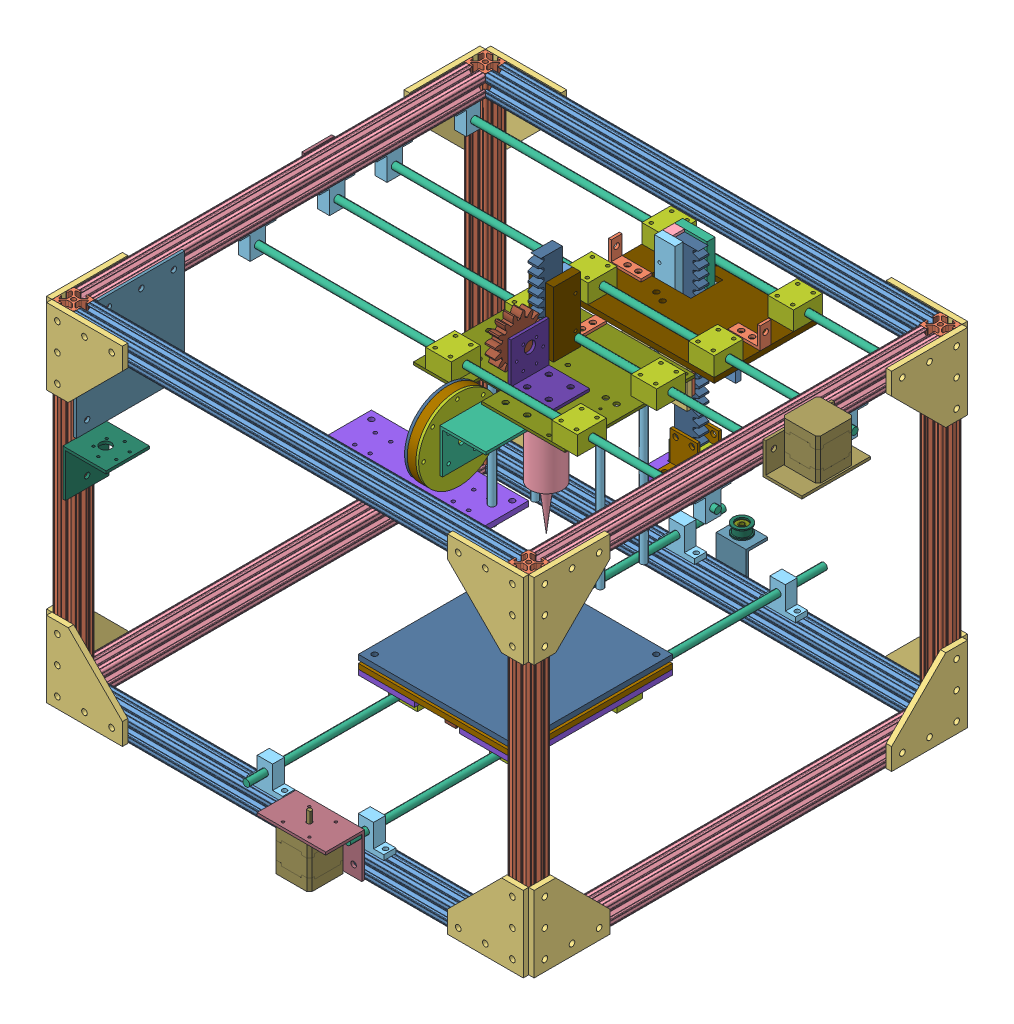
SolidWorks assembly V2, configuration Default. Lengths in mm.
Overall size (631.82 453.25 588.02).
124 component instances, 46 part files, 45 mates.
Components (placement in the parent):
- frame_asm-1: frame_asm [Default] at (279.5484 -24.8965 33.4997) size (571.5 406.4 520.7)
  - 8020-20in-3: 8020-20in [Default] at (-420.1656 190.7852 170.939) x (0 0 1) z (-1 0 0) size (25.4 25.4 508)
  - 8020-20in-4: 8020-20in [Default] at (-420.1656 190.7852 653.539) x (0 0 1) z (-1 0 0) size (25.4 25.4 508)
  - 8020-12in-1: 8020-12in [Default] at (-432.8656 178.0852 653.539) x (1 0 0) z (0 -1 0) size (25.4 25.4 406.4)
  - 8020-12in-2: 8020-12in [Default] at (100.5344 178.0852 653.539) x (-1 0 0) z (0 -1 0) size (25.4 25.4 406.4)
  - 8020-12in-3: 8020-12in [Default] at (-432.8656 584.4852 170.939) x (-1 0 0) z (0 1 0) size (25.4 25.4 406.4)
  - 8020-12in-4: 8020-12in [Default] at (100.5344 584.4852 170.939) x (-1 0 0) z (0 1 0) size (25.4 25.4 406.4)
  - 8020-20in-7: 8020-20in [Default] at (-420.1656 571.7852 653.539) x (0 0 1) z (-1 0 0) size (25.4 25.4 508)
  - 8020-20in-8: 8020-20in [Default] at (-420.1656 571.7852 170.939) x (0 0 1) z (-1 0 0) size (25.4 25.4 508)
  - corner bracket-1: corner bracket [Default] at (113.2344 178.0852 672.589) x (-1 0 0) z (0 0 -1) size (88.9 88.9 6.35)
  - corner bracket-2: corner bracket [Default] at (113.2344 584.4852 666.239) x (-1 0 0) z (0 0 1) size (88.9 88.9 6.35)
  - corner bracket-3: corner bracket [Default] at (119.5844 584.4852 666.239) x (0 0 -1) z (-1 0 0) size (88.9 88.9 6.35)
  - corner bracket-4: corner bracket [Default] at (113.2344 178.0852 666.239) x (0 0 -1) z (1 0 0) size (88.9 88.9 6.35)
  - corner bracket-5: corner bracket [Default] at (119.5844 178.0852 158.239) x (0 0 1) z (-1 0 0) size (88.9 88.9 6.35)
  - corner bracket-6: corner bracket [Default] at (113.2344 178.0852 158.239) x (-1 0 0) z (0 0 -1) size (88.9 88.9 6.35)
  - corner bracket-7: corner bracket [Default] at (113.2344 584.4852 151.889) x (-1 0 0) z (0 0 1) size (88.9 88.9 6.35)
  - corner bracket-8: corner bracket [Default] at (113.2344 584.4852 158.239) x (0 0 1) z (1 0 0) size (88.9 88.9 6.35)
  - corner bracket-9: corner bracket [Default] at (-445.5656 178.0852 666.239) size (88.9 88.9 6.35)
  - corner bracket-10: corner bracket [Default] at (-451.9156 178.0852 666.239) x (0 0 -1) z (1 0 0) size (88.9 88.9 6.35)
  - corner bracket-11: corner bracket [Default] at (-445.5656 584.4852 672.589) x (1 0 0) z (0 0 -1) size (88.9 88.9 6.35)
  - corner bracket-12: corner bracket [Default] at (-445.5656 584.4852 666.239) x (0 0 -1) z (-1 0 0) size (88.9 88.9 6.35)
  - corner bracket-13: corner bracket [Default] at (-445.5656 178.0852 151.889) size (88.9 88.9 6.35)
  - corner bracket-14: corner bracket [Default] at (-445.5656 178.0852 158.239) x (0 0 1) z (-1 0 0) size (88.9 88.9 6.35)
  - corner bracket-15: corner bracket [Default] at (-445.5656 584.4852 158.239) x (0 -1 0) z (-1 0 0) size (88.9 88.9 6.35)
  - corner bracket-16: corner bracket [Default] at (-445.5656 584.4852 158.239) x (1 0 0) z (0 0 -1) size (88.9 88.9 6.35)
  - 8020-18in-1: 8020-18in [Default] at (100.5344 190.7852 640.839) size (25.4 25.4 457.2)
  - 8020-18in-2: 8020-18in [Default] at (100.5344 571.7852 640.839) size (25.4 25.4 457.2)
  - 8020-18in-3: 8020-18in [Default] at (-432.8656 571.7852 640.839) size (25.4 25.4 457.2)
  - 8020-18in-4: 8020-18in [Default] at (-432.8656 190.7852 640.839) size (25.4 25.4 457.2)
- rails_asm-bottom-1: rails_asm-bottom [Default] at (188.2466 178.4066 647.1595) size (184.15 52.16 558.8)
  - Linear Rail Shaft Guide-1: Linear Rail Shaft Guide [Default] at (-12.9326 0.1821 32.8794) size (42 32.8 14)
  - Linear Rail Shaft Guide-2: Linear Rail Shaft Guide [Default] at (-12.9326 0.1821 -449.7206) size (42 32.8 14)
  - Linear Rail Shaft Guide-3: Linear Rail Shaft Guide [Default] at (-131.3326 0.1821 32.8794) size (42 32.8 14)
  - Linear Rail Shaft Guide-4: Linear Rail Shaft Guide [Default] at (-131.3326 0.1821 -449.7206) size (42 32.8 14)
  - 8mm rod-1: 8mm rod [Default] at (8.0674 20.1821 -489.9705) x (0.986971 -0.1609 0) z (0 0 1) size (8 8 558.8)
  - 8mm rod-2: 8mm rod [Default] at (-110.3326 20.1821 -489.9705) x (0.967966 -0.251082 0) z (0 0 1) size (8 8 558.8)
  - linear bearing platform-1: linear bearing platform [Default] at (-8.9326 9.1821 -144.8893) size (34 22 30)
  - linear bearing platform-2: linear bearing platform [Default] at (-8.9326 9.1821 -260.2393) size (34 22 30)
  - linear bearing platform-3: linear bearing platform [Default] at (-127.3326 9.1821 -144.8893) size (34 22 30)
  - linear bearing platform-4: linear bearing platform [Default] at (-127.3326 9.1821 -260.2393) size (34 22 30)
  - bottom plate-1: bottom plate [Default] at (-24.8076 37.1765 -279.6393) x (1 0 0) z (0 -1 0) size (65.75 184.15 5.99)
  - bottom plate-2: bottom plate [Default] at (-143.2076 37.1765 -279.6393) x (1 0 0) z (0 -1 0) size (65.75 184.15 5.99)
  - middle plate-1: middle plate [Default] at (-143.2076 37.1765 -95.4893) x (1 0 0) z (0 1 0) size (184.15 184.15 5.99)
  - top layer-1: top layer [Default] at (-143.2076 46.3459 -95.4893) x (1 0 0) z (0 1 0) size (184.15 184.15 5.99)
  - L-bracket belt mount-1: L-bracket belt mount [Default] at (-51.1326 37.1765 -257.4143) x (0 -1 0) z (-1 0 0) size (25.4 28.57 12.7)
  - L-bracket belt mount-2: L-bracket belt mount [Default] at (-63.8326 37.1765 -117.7143) x (0 -1 0) z (1 0 0) size (25.4 28.57 12.7)
- stepper motor-1: stepper motor [Default] at (160.1312 153.1887 724.0637) x (-1 0 0) z (0 1 0) size (42.3 42.3 63.5)
- L-bracket motor mount-1: L-bracket motor mount [Default] at (200.3312 153.1887 699.7387) x (0 0 1) z (-1 0 0) size (45.48 51.17 80.4)
- L-bracket idler mount-1: L-bracket idler mount [Default] at (104.6172 153.1887 191.7387) x (0 0 -1) z (1 0 0) size (25.4 51.17 34.92)
- idler pulley-1: idler pulley [Default] at (122.0797 211.3637 179.0387) x (0 -1 0) z (0.480075 0 0.877227) size (12.6 21 21)
  - B17023-1: B17023 [Default] at origin size (11.2 21 21)
  - BEARING_5_16_5-1: BEARING_5_16_5 [Default] at (-1.5 0 0) x (0 1 0) z (0 0 1) size (16 5 16)
  - B18026-1: B18026 [Default] at (2 0 0) x (0 1 0) z (0 0 1) size (10 1 10)
  - BEARING_5_16_5-2: BEARING_5_16_5 [Default] at (4.5 0 0) x (0 1 0) z (0 0 1) size (16 5 16)
- part placer asm-1: part placer asm [Default] at (270.0393 672.9206 180.4038) x (0 0 1) z (0 -1 0) size (135 558.8 245.72)
  - mounting plate-1: mounting plate [Default] at (27.1569 24.9758 169.7319) size (127 177.8 5.99)
  - front motor plate-1: front motor plate [Default] at (90.8368 139.2758 175.7263) x (0 -1 0) z (-1 0 0) size (76.2 50.8 5.99)
  - gearmotor mounting brackets-1: gearmotor mounting brackets [Default] at (141.8424 75.7758 175.7263) x (0 0 1) z (0 -1 0) size (38.1 25.4 12.7)
  - rear motor plate-1: rear motor plate [Default] at (147.8368 139.2758 175.7263) x (0 -1 0) z (-1 0 0) size (76.2 50.8 5.99)
  - rack back plate-1: rack back plate [Default] at (62.2477 151.5948 255.1013) x (1 0 0) z (0 1 0) size (13.97 127 11.81)
  - rack right plate-1: rack right plate [Default] at (85.7427 163.4058 255.1013) x (-1 0 0) z (0 -1 0) size (9.53 127 24.13)
  - rack left plate-1: rack left plate [Default] at (62.2477 163.4058 255.1013) x (-1 0 0) z (0 -1 0) size (9.53 127 38.1)
  - gearmotor mounting brackets-2: gearmotor mounting brackets [Default] at (141.8424 139.2758 175.7263) x (0 0 1) z (0 -1 0) size (38.1 25.4 12.7)
  - gearmotor mounting brackets-3: gearmotor mounting brackets [Default] at (90.8368 126.5758 175.7263) x (0 0 1) z (0 1 0) size (38.1 25.4 12.7)
  - gearmotor mounting brackets-4: gearmotor mounting brackets [Default] at (90.8368 63.0758 175.7263) x (0 0 1) z (0 1 0) size (38.1 25.4 12.7)
  - gearmotor mounting brackets-5: gearmotor mounting brackets [Default] at (85.7427 139.2758 175.7263) x (0 0 1) z (0 1 0) size (38.1 25.4 12.7)
  - gearmotor mounting brackets-6: gearmotor mounting brackets [Default] at (52.7227 144.3558 175.7263) x (0 0 1) z (0 -1 0) size (38.1 25.4 12.7)
  - rails_asm-1: rails_asm [Default] at (129.0895 -70.2762 138.5497) x (1 0 0) z (0 -1 0) size (135 32.8 558.8)
    - Linear Rail Shaft Guide-1: Linear Rail Shaft Guide [Default] at (-12.9326 0.1821 32.8794) size (42 32.8 14)
    - Linear Rail Shaft Guide-2: Linear Rail Shaft Guide [Default] at (-12.9326 0.1821 -500.7446) size (42 32.8 14)
    - Linear Rail Shaft Guide-3: Linear Rail Shaft Guide [Default] at (-105.9326 0.1821 32.8794) size (42 32.8 14)
    - Linear Rail Shaft Guide-4: Linear Rail Shaft Guide [Default] at (-105.9326 0.1821 -500.7446) size (42 32.8 14)
    - 8mm rod-1: 8mm rod [Default] at (8.0674 20.1821 -506.1132) x (0.336006 0.94186 0) z (0 0 1) size (8 8 558.8)
    - 8mm rod-2: 8mm rod [Default] at (-84.9326 20.1821 -506.1132) x (0.967966 -0.251082 0) z (0 0 1) size (8 8 558.8)
    - linear bearing platform-1: linear bearing platform [Default] at (-8.9326 9.1821 -125.252) size (34 22 30)
    - linear bearing platform-2: linear bearing platform [Default] at (-8.9326 9.1821 -273.052) size (34 22 30)
    - linear bearing platform-3: linear bearing platform [Default] at (-101.9326 9.1821 -125.252) size (34 22 30)
    - linear bearing platform-4: linear bearing platform [Default] at (-101.9326 9.1821 -273.052) size (34 22 30)
  - gearmotor mounting brackets-8: gearmotor mounting brackets [Default] at (87.4819 202.7758 169.7319) x (0 -1 0) z (1 0 0) size (38.1 25.4 12.7)
  - gearmotor mounting brackets-9: gearmotor mounting brackets [Default] at (100.1819 24.9758 169.7319) x (0 1 0) z (-1 0 0) size (38.1 25.4 12.7)
  - servo-1: servo [Default] at (57.8567 153.533 334.3104) x (0 -0.999999 -0.00124) z (0 -0.00124 0.999999) size (52.33 20.5 39.5)
  - servo mount-1: servo mount [Default] at (57.1067 155.0052 356.7659) x (0 -0.999999 -0.00124) z (0 -0.00124 0.999999) size (61 72.8 5.99)
  - servo mounting brackets-1: servo mounting brackets [Default] at (57.1067 116.6302 356.7183) x (0 0.00124 -0.999999) z (0 0.999999 0.00124) size (38.1 25.4 31.75)
  - servo mounting brackets-2: servo mounting brackets [Default] at (79.1067 148.3802 356.7576) x (0 0.00124 -0.999999) z (0 -0.999999 -0.00124) size (38.1 25.4 31.75)
  - rack spur rectangular_ai-2: rack spur rectangular_ai [Inch - Rack-spur - rectangular 8DP 20PA 0.465FW 1PH 8L---SAll] at (62.2477 151.5948 334.2962) x (0 0 -1) z (-1 0 0) size (203.2 28.57 11.81)
  - spur gear_ai-2: spur gear_ai [Inch - Spur gear 8DP 16T 20PA 0.465FW ---S16N3.0H2.0L0.03125N] at (62.2477 101.1758 208.1263) size (11.81 56.32 56.32)
- L-bracket motor mount-part placer-1: L-bracket motor mount-part placer [Default] at (392.7829 559.5887 424.9822) x (1 0 0) z (0 0 -1) size (45.48 38.1 80.4)
- stepper motor-2: stepper motor [Default] at (417.1079 574.6637 384.7822) x (1 0 0) z (0 -1 0) size (42.3 42.3 63.5)
- L-bracket idler mount-part placer-1: L-bracket idler mount-part placer [Default] at (-166.0171 559.5887 368.7318) x (-1 0 0) z (0 0 1) size (25.4 38.1 34.92)
- B17023-1: B17023 [Default] at (-178.7171 515.8887 386.1943) x (0 1 0) z (-0.715602 0 -0.698508) size (11.2 21 21)
- bolt cutter plate-1: bolt cutter plate [Default] at (-140.6171 432.5887 699.7387) x (0 0 -1) z (1 0 0) size (127 127 3.17)
- l-bracket gearmotor wire cutter-1: l-bracket gearmotor wire cutter [Default] at (-89.8171 429.831 661.6387) x (0 0 1) z (0 -1 0) size (50.8 50.8 53.98)
- flux wire asm-1: flux wire asm [Default] at (-137.6892 649.3389 517.6928) x (0 0 -1) z (1 0 0) size (156.4 287.4 558.8)
  - flux-wire rails base-1: flux-wire rails base [Default] at (22.7321 -149.3252 368.4326) x (1 0 0) z (0 1 0) size (152.4 177.8 3.17)
  - front motor plate-flux extruder-1: front motor plate-flux extruder [Default] at (95.7571 -146.1502 276.3576) x (-1 0 0) z (0 0 -1) size (44.45 50.8 50.8)
  - rack side plates-1: rack side plates [Default] at (136.1558 -146.1502 263.6576) x (0 0 1) z (-1 0 0) size (9.53 76.2 31.75)
  - rack back plate - flux-1: rack back plate - flux [Default] at (136.1431 -146.1502 254.1326) x (0 0 1) z (-1 0 0) size (9.53 76.2 11.81)
  - rack side plates-2: rack side plates [Default] at (136.1558 -146.1502 244.6076) x (0 0 1) z (-1 0 0) size (9.53 76.2 31.75)
  - rear rack brace l bracket-1: rear rack brace l bracket [Default] at (136.1558 -146.1502 265.2451) x (0 1 0) z (0 0 -1) size (38.1 38.1 12.7)
  - rack spur rectangular_ai-3: rack spur rectangular_ai [Inch - Rack-spur - rectangular 8DP 20PA 0.465FW 1PH 6L---SAll] at (124.3321 -195.3037 263.6576) x (0 1 0) z (0 0 1) size (152.4 28.57 11.81)
  - spur gear_ai-2: spur gear_ai [Inch - Spur gear 8DP 16T 20PA 0.465FW ---S16N3.0H2.0L0.03125N] at (73.5321 -113.7502 263.6576) x (0 0 -1) z (1 0 0) size (11.81 56.32 56.32)
  - syringe piston-1: syringe piston [Default] at (110.2123 -169.9037 258.8957) x (1 0 0) z (0 -1 0) size (34.92 34.92 25.4)
  - syringe-1: syringe [Default] at (110.2123 -152.5002 258.8957) x (-0.006602 0 0.999978) z (0 -1 0) size (63.5 41.27 180.98)
  - large 8mm standoff-1: large 8mm standoff [Default] at (84.6446 -327.1252 347.7951) x (1 0 0) z (0 1 0) size (8 8 177.8)
  - large 8mm standoff-2: large 8mm standoff [Default] at (84.6446 -327.1252 220.7951) x (1 0 0) z (0 1 0) size (8 8 177.8)
  - large 8mm standoff-3: large 8mm standoff [Default] at (135.4446 -327.1252 347.7951) x (1 0 0) z (0 1 0) size (8 8 177.8)
  - large 8mm standoff-4: large 8mm standoff [Default] at (135.4446 -327.1252 220.7951) x (1 0 0) z (0 1 0) size (8 8 177.8)
  - bottom plate-1: bottom plate [Default] at (43.862 -306.516 54.4966) x (1 0 0) z (0 -1 0) size (65.75 184.15 5.99)
  - rails_asm-flux-3: rails_asm-flux [Default] at (47.7995 -114.9681 478.0047) x (-1 0 0) z (0 0 1) size (135 32.8 558.8)
    - Linear Rail Shaft Guide-1: Linear Rail Shaft Guide [Default] at (-12.9326 0.1821 32.8794) size (42 32.8 14)
    - Linear Rail Shaft Guide-2: Linear Rail Shaft Guide [Default] at (-12.9326 0.1821 -500.7446) size (42 32.8 14)
    - Linear Rail Shaft Guide-3: Linear Rail Shaft Guide [Default] at (-105.9326 0.1821 32.8794) size (42 32.8 14)
    - Linear Rail Shaft Guide-4: Linear Rail Shaft Guide [Default] at (-105.9326 0.1821 -500.7446) size (42 32.8 14)
    - 8mm rod-1: 8mm rod [Default] at (8.0674 20.1821 -506.1132) x (0.336006 0.94186 0) z (0 0 1) size (8 8 558.8)
    - 8mm rod-2: 8mm rod [Default] at (-84.9326 20.1821 -506.1132) x (0.967966 -0.251082 0) z (0 0 1) size (8 8 558.8)
    - linear bearing platform-1: linear bearing platform [Default] at (-8.9326 9.1821 -125.252) size (34 22 30)
    - linear bearing platform-2: linear bearing platform [Default] at (-8.9326 9.1821 -273.052) size (34 22 30)
    - linear bearing platform-3: linear bearing platform [Default] at (-101.9326 9.1821 -125.252) size (34 22 30)
    - linear bearing platform-4: linear bearing platform [Default] at (-101.9326 9.1821 -273.052) size (34 22 30)
- l-bracket gearmotor revolver-3: l-bracket gearmotor revolver [Default] at (129.7784 449.2137 540.9347) x (0 0 -1) z (1 0 0) size (94.23 50.8 53.98)
- Revolver_motor_plate-3: Revolver_motor_plate [Default] at (129.7784 442.8322 500.8431) x (0 0 1) z (-1 0 0) size (95.25 95.25 3.17)
- Revolver_45deg-2: Revolver_45deg [Default] at (116.4434 474.6137 518.0747) x (0 0 -1) z (1 0 0) size (76.2 76.2 10.16)
- Revolver_motor_plate_middle-2: Revolver_motor_plate_middle [Default] at (116.4434 442.0073 533.6893) x (0 0.050197 -0.998739) z (1 0 0) size (95.25 95.25 10.16)
- Revolver_motor_plate2-1: Revolver_motor_plate2 [Default] at (116.4434 443.7373 499.2695) x (0 -0.050197 0.998739) z (-1 0 0) size (95.25 71.44 3.17)
Mates (geometry in assembly coordinates):
- Coincident8: coincident aligned: plane of frame_asm-1/8020-20in-4 through (367.3829 153.1887 693.3718) normal (0 -1 0); plane of stepper motor-1 through (138.9812 153.1887 745.2137) normal (0 -1 0)
- Coincident6: coincident anti-aligned: plane of frame_asm-1/8020-20in-4 through (367.3829 178.5887 696.5891) normal (0 1 0); plane of rails_asm-bottom-1/Linear Rail Shaft Guide-1 through (175.314 178.5887 694.0389) normal (0 -1 0)
- Distance1: distance = 5.6998 mm aligned: plane of rails_asm-bottom-1/Linear Rail Shaft Guide-1 through (175.314 178.5887 694.0389) normal (0 0 1); plane of frame_asm-1/8020-20in-4 through (367.3829 172.2218 699.7387) normal (0 0 1)
- Coincident9: coincident anti-aligned: plane of frame_asm-1/8020-20in-4 through (367.3829 172.2218 699.7387) normal (0 0 1); plane of L-bracket motor mount-1 through (119.9312 153.1887 699.7387) normal (0 0 -1)
- Coincident10: coincident aligned: plane of frame_asm-1/corner bracket-9 through (-166.0171 153.1887 706.0887) normal (0 -1 0); plane of L-bracket motor mount-1 through (119.9312 153.1887 699.7387) normal (0 -1 0)
- Concentric1: concentric anti-aligned: cylinder of stepper motor-1 through (160.1312 216.6887 724.0637) axis (0 -1 0) radius 2.5; cylinder of L-bracket motor mount-1 through (160.1312 153.1887 724.0637) axis (0 1 0) radius 3
- Coincident11: coincident aligned: plane of stepper motor-1 through (181.2812 201.1887 745.2137) normal (0 0 1); plane of L-bracket motor mount-1 through (119.9312 201.1887 745.2137) normal (0 0 1)
- Coincident12: coincident anti-aligned: plane of frame_asm-1/8020-20in-3 through (367.3829 156.3383 191.7387) normal (0 0 -1); plane of L-bracket idler mount-1 through (139.5422 153.1887 191.7387) normal (0 0 1)
- Coincident13: coincident aligned: plane of frame_asm-1/8020-20in-3 through (367.3829 153.1887 198.1055) normal (0 -1 0); plane of L-bracket idler mount-1 through (139.5422 153.1887 191.7387) normal (0 -1 0)
- Concentric4: concentric anti-aligned: cylinder of L-bracket idler mount-1 through (122.0797 153.1887 179.0387) axis (0 1 0) radius 2.5; cylinder of idler pulley-1/BEARING_5_16_5-1 through (122.0797 215.6137 179.0387) axis (0 -1 0) radius 2.5
- Coincident14: coincident anti-aligned: plane of L-bracket idler mount-1 through (139.5422 204.3637 191.7387) normal (0 1 0); plane of idler pulley-1/BEARING_5_16_5-2 through (122.0797 204.3637 179.0387) normal (0 -1 0)
- Coincident15: coincident anti-aligned: plane of frame_asm-1/8020-18in-3 through (-146.984 534.1887 217.1387) normal (0 -1 0); plane of part placer asm-1/rails_asm-1/Linear Rail Shaft Guide-4 through (-146.4291 534.1887 203.5607) normal (0 1 0)
- Distance2: distance = 5.588 mm aligned: plane of part placer asm-1/rails_asm-1/Linear Rail Shaft Guide-2 through (-160.4291 534.1887 296.5607) normal (-1 0 0); plane of frame_asm-1/8020-18in-3 through (-166.0171 537.3383 217.1387) normal (-1 0 0)
- Coincident19: coincident anti-aligned: plane of frame_asm-1/8020-18in-2 through (392.7829 537.3383 217.1387) normal (1 0 0); plane of L-bracket motor mount-part placer-1 through (392.7829 559.5887 344.5822) normal (-1 0 0)
- Coincident20: coincident aligned: plane of frame_asm-1/corner bracket-8 through (399.1329 559.5887 191.7387) normal (0 1 0); plane of L-bracket motor mount-part placer-1 through (392.7829 559.5887 344.5822) normal (0 1 0)
- Coincident21: coincident anti-aligned: plane of L-bracket motor mount-part placer-1 through (438.2579 524.6637 344.5822) normal (0 1 0); plane of stepper motor-2 through (417.1079 524.6637 384.7822) normal (0 -1 0)
- Coincident22: coincident anti-aligned: plane of L-bracket motor mount-part placer-1 through (395.9579 559.5887 344.5822) normal (1 0 0); plane of stepper motor-2 through (395.9579 526.6637 363.6322) normal (-1 0 0)
- Concentric5: concentric anti-aligned: cylinder of L-bracket motor mount-part placer-1 through (417.1079 559.5887 384.7822) axis (0 -1 0) radius 3; cylinder of stepper motor-2 through (417.1079 511.1637 384.7822) axis (0 1 0) radius 2.5
- Coincident23: coincident anti-aligned: plane of frame_asm-1/8020-18in-3 through (-166.0171 537.3383 217.1387) normal (-1 0 0); plane of L-bracket idler mount-part placer-1 through (-166.0171 559.5887 403.6568) normal (1 0 0)
- Coincident24: coincident aligned: plane of frame_asm-1/corner bracket-12 through (-172.3671 559.5887 699.7387) normal (0 1 0); plane of L-bracket idler mount-part placer-1 through (-166.0171 559.5887 403.6568) normal (0 1 0)
- Coincident25: coincident anti-aligned: plane of L-bracket idler mount-part placer-1 through (-166.0171 521.4887 403.6568) normal (0 -1 0); plane of B17023-1 through (-178.7171 521.4887 386.1943) normal (0 1 0)
- Concentric6: concentric aligned: cylinder of L-bracket idler mount-part placer-1 through (-178.7171 559.5887 386.1943) axis (0 -1 0) radius 2.5; cylinder of B17023-1 through (-178.7171 522.0487 386.1943) axis (0 -1 0) radius 7.975
- Coincident66: coincident anti-aligned: plane of frame_asm-1/8020-18in-3 through (-140.6171 537.3383 217.1387) normal (1 0 0); plane of bolt cutter plate-1 through (-140.6171 432.5887 699.7387) normal (-1 0 0)
- Coincident67: coincident aligned: plane of frame_asm-1/8020-18in-3 through (-143.7667 559.5887 217.1387) normal (0 1 0); plane of bolt cutter plate-1 through (-137.4421 559.5887 674.3387) normal (0 1 0)
- Coincident68: coincident aligned: plane of frame_asm-1/8020-20in-7 through (367.3829 537.3383 699.7387) normal (0 0 1); plane of bolt cutter plate-1 through (-137.4421 432.5887 699.7387) normal (0 0 1)
- Coincident73: coincident anti-aligned: plane of frame_asm-1/8020-12in-1 through (-140.6171 559.5887 677.4883) normal (1 0 0); plane of l-bracket gearmotor wire cutter-1 through (-140.6171 426.656 661.6387) normal (-1 0 0)
- Distance26: distance = 12.7 mm aligned: plane of l-bracket gearmotor wire cutter-1 through (-89.8171 426.656 661.6387) normal (0 0 -1); plane of frame_asm-1/8020-12in-1 through (-146.984 559.5887 674.3387) normal (0 0 -1)
- Distance27: distance = 25.4 mm anti-aligned: plane of part placer asm-1/rails_asm-1/Linear Rail Shaft Guide-2 through (-146.4291 534.1887 338.5607) normal (0 0 1); plane of flux wire asm-1/rails_asm-flux-3/Linear Rail Shaft Guide-4 through (-146.4291 534.1887 363.9607) normal (0 0 -1)
- Coincident76: coincident anti-aligned: plane of frame_asm-1/8020-18in-3 through (-159.6503 534.1887 217.1387) normal (0 -1 0); plane of flux wire asm-1/rails_asm-flux-3/Linear Rail Shaft Guide-4 through (-146.4291 534.1887 363.9607) normal (0 1 0)
- Parallel2: parallel anti-aligned: line of part placer asm-1/rails_asm-1/Linear Rail Shaft Guide-2 through (-160.4291 501.3887 326.5607) axis (0 0 -1); line of flux wire asm-1/rails_asm-flux-3/Linear Rail Shaft Guide-4 through (-160.4291 534.1887 363.9607) axis (0 0 1)
- Coincident78: coincident aligned: plane of part placer asm-1/rails_asm-1/Linear Rail Shaft Guide-2 through (-160.4291 534.1887 296.5607) normal (-1 0 0); plane of flux wire asm-1/rails_asm-flux-3/Linear Rail Shaft Guide-4 through (-160.4291 534.1887 363.9607) normal (-1 0 0)
- Concentric19: concentric anti-aligned: cylinder of flux wire asm-1/front motor plate-flux extruder-1 through (148.1934 503.1887 456.8607) axis (0 1 0) radius 3.175; cylinder of l-bracket gearmotor revolver-3 through (148.1934 500.0137 456.8607) axis (0 -1 0) radius 3.175
- Concentric20: concentric aligned: cylinder of flux wire asm-1/flux-wire rails base-1 through (173.5934 503.1887 482.2607) axis (0 -1 0) radius 3.175; cylinder of l-bracket gearmotor revolver-3 through (173.5934 500.0137 482.2607) axis (0 -1 0) radius 3.175
- Coincident85: coincident anti-aligned: plane of flux wire asm-1/flux-wire rails base-1 through (230.7434 500.0137 494.9607) normal (0 -1 0); plane of l-bracket gearmotor revolver-3 through (132.9534 500.0137 540.9347) normal (0 1 0)
- Coincident86: coincident anti-aligned: plane of l-bracket gearmotor revolver-3 through (129.7784 449.2137 540.9347) normal (-1 0 0); plane of Revolver_motor_plate-3 through (129.7784 474.6137 518.0747) normal (1 0 0)
- Coincident87: coincident anti-aligned: plane of Revolver_motor_plate-3 through (126.6034 474.6137 518.0747) normal (-1 0 0); plane of Revolver_45deg-2 through (126.6034 474.6137 518.0747) normal (1 0 0)
- Concentric23: concentric anti-aligned: cylinder of Revolver_motor_plate-3 through (126.6034 474.6137 518.0747) axis (1 0 0) radius 4; cylinder of Revolver_45deg-2 through (126.6034 474.6137 518.0747) axis (-1 0 0) radius 3
- Concentric25: concentric anti-aligned: cylinder of l-bracket gearmotor revolver-3 through (132.9534 490.1137 502.5747) axis (-1 0 0) radius 2; cylinder of Revolver_motor_plate-3 through (126.6034 490.1137 502.5747) axis (1 0 0) radius 2
- Concentric26: concentric anti-aligned: cylinder of l-bracket gearmotor revolver-3 through (132.9534 490.1137 533.5747) axis (-1 0 0) radius 2; cylinder of Revolver_motor_plate-3 through (126.6034 490.1137 533.5747) axis (1 0 0) radius 2
- Coincident88: coincident anti-aligned: plane of Revolver_motor_plate-3 through (126.6034 474.6137 518.0747) normal (-1 0 0); plane of Revolver_motor_plate_middle-2 through (126.6034 474.6137 518.0747) normal (1 0 0)
- Concentric29: concentric anti-aligned: cylinder of Revolver_motor_plate-3 through (129.7784 476.7175 476.2176) axis (-1 0 0) radius 2.0828; cylinder of Revolver_motor_plate_middle-2 through (116.4434 476.7175 476.2176) axis (1 0 0) radius 2.0828
- Concentric30: concentric anti-aligned: cylinder of Revolver_motor_plate-3 through (129.7784 472.5099 559.9319) axis (-1 0 0) radius 2.0828; cylinder of Revolver_motor_plate_middle-2 through (116.4434 472.5099 559.9319) axis (1 0 0) radius 2.0828
- Concentric31: concentric anti-aligned: cylinder of Revolver_motor_plate_middle-2 through (116.4434 476.7175 476.2176) axis (1 0 0) radius 2.0828; cylinder of Revolver_motor_plate2-1 through (116.4434 476.7175 476.2176) axis (-1 0 0) radius 2.0828
- Concentric32: concentric anti-aligned: cylinder of Revolver_motor_plate_middle-2 through (116.4434 472.5099 559.9319) axis (1 0 0) radius 2.0828; cylinder of Revolver_motor_plate2-1 through (116.4434 472.5099 559.9319) axis (-1 0 0) radius 2.0828
- Coincident89: coincident anti-aligned: plane of Revolver_45deg-2 through (116.4434 474.6137 518.0747) normal (-1 0 0); plane of Revolver_motor_plate2-1 through (116.4434 474.6137 518.0747) normal (1 0 0)
